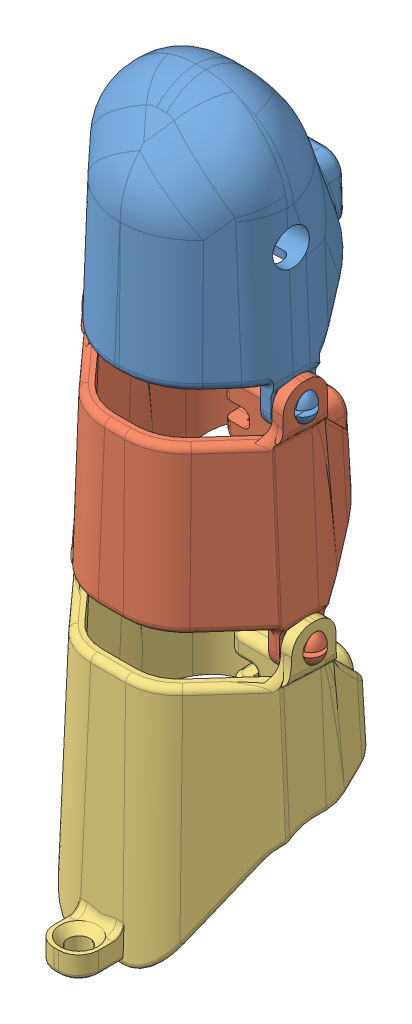
SolidWorks assembly finger_pinky, configuration Default. Lengths in mm.
Overall size (26.85 82.66 29.58).
3 component instances, 3 part files, 6 mates.
Components (placement in the parent):
- pinky_distal-1: pinky_distal [Default] at (-15.2603 -12.8436 -7.9474) x (1 0 0) z (0 -0.002557 0.999997) size (24.82 30.95 21.46)
- pinky_middle-1: pinky_middle [Default] at (-15.3493 -12.2721 -7.9459) x (1 0 0) z (0 -0.002557 0.999997) size (26.85 28.58 22.66)
- pinky_proximal-1: pinky_proximal [Default] at (-15.4493 -10.7743 -7.8979) size (25.27 33.29 29.58)
Mates (geometry in assembly coordinates):
- Concentric2: concentric anti-aligned: circle of pinky_middle-1; circle of pinky_proximal-1
- Distance2: distance = 0.127 mm anti-aligned: plane of pinky_middle-1 through (6.9787 3.93 13.1309) normal (1 0 0); plane of pinky_proximal-1 through (7.1057 9.0377 14.2464) normal (-1 0 0)
- Concentric3: concentric anti-aligned: circle of pinky_distal-1; circle of pinky_middle-1
- Distance3: distance = 0.127 mm anti-aligned: plane of pinky_middle-1 through (6.1907 32.5027 14.0634) normal (-1 0 0); plane of pinky_distal-1 through (6.0637 27.4262 12.7043) normal (1 0 0)
- Parallel3: parallel aligned: plane of pinky_distal-1 through (8.4767 30.3069 3.6361) normal (0 -0.999997 -0.002557); plane of pinky_middle-1 through (9.3917 6.7485 3.5758) normal (0 -0.999997 -0.002557)
- Parallel4: parallel aligned: plane of pinky_middle-1 through (0.8228 14.5847 -9.5122) normal (0 -0.999502 -0.031556); plane of pinky_proximal-1 through (0.7559 -11.2602 -10.3274) normal (0 -0.999502 -0.031556)
